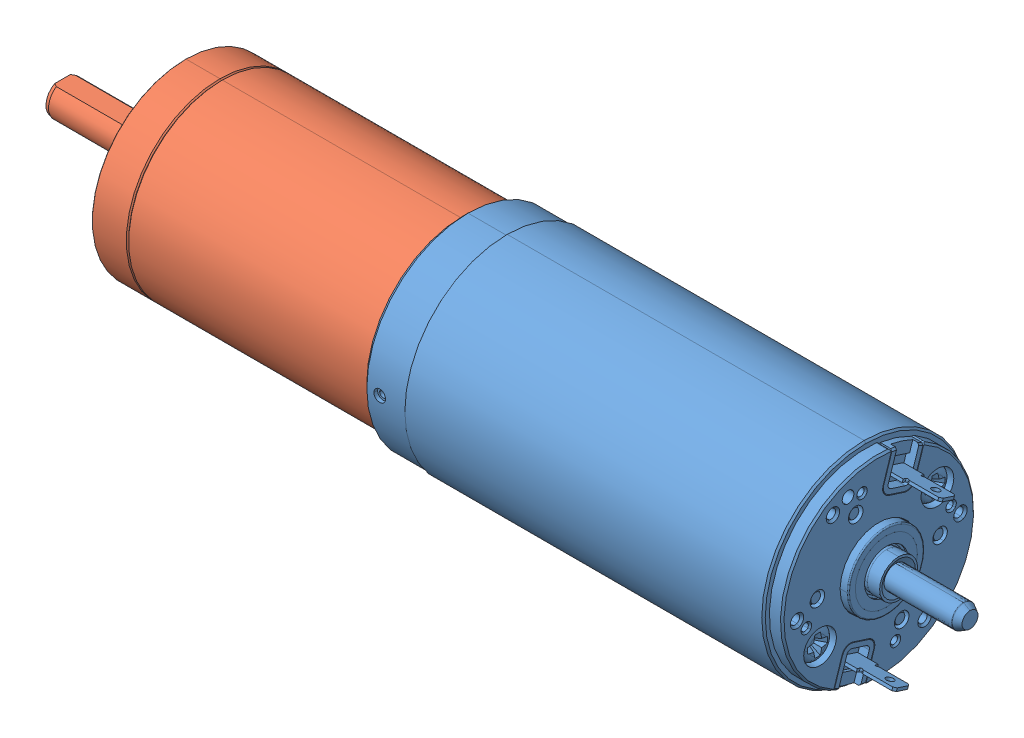
SolidWorks assembly gear_motor_mate, configuration Default. Lengths in mm.
Overall size (155.1 35 35).
2 component instances, 2 part files, 2 mates.
Components (placement in the parent):
- 273752_RE35_GB_90W_KL_2WE.stp-1: 273752_RE35_GB_90W_KL_2WE.stp [Default] at origin size (106.6 35 35)
- 166187_GP32A-5st-3: 166187_GP32A-5st [Default] at (-62.77 0 0) size (77.5 32 32)
Mates (geometry in assembly coordinates):
- 重合3: coincident: plane of 273752_RE35_GB_90W_KL_2WE.stp-1 through (-15.27 0 0) normal (-1 0 0); plane of 166187_GP32A-5st-3 through (-15.27 0 0) normal (1 0 0)
- 同心4: concentric: circle of 273752_RE35_GB_90W_KL_2WE.stp-1; circle of 166187_GP32A-5st-3
